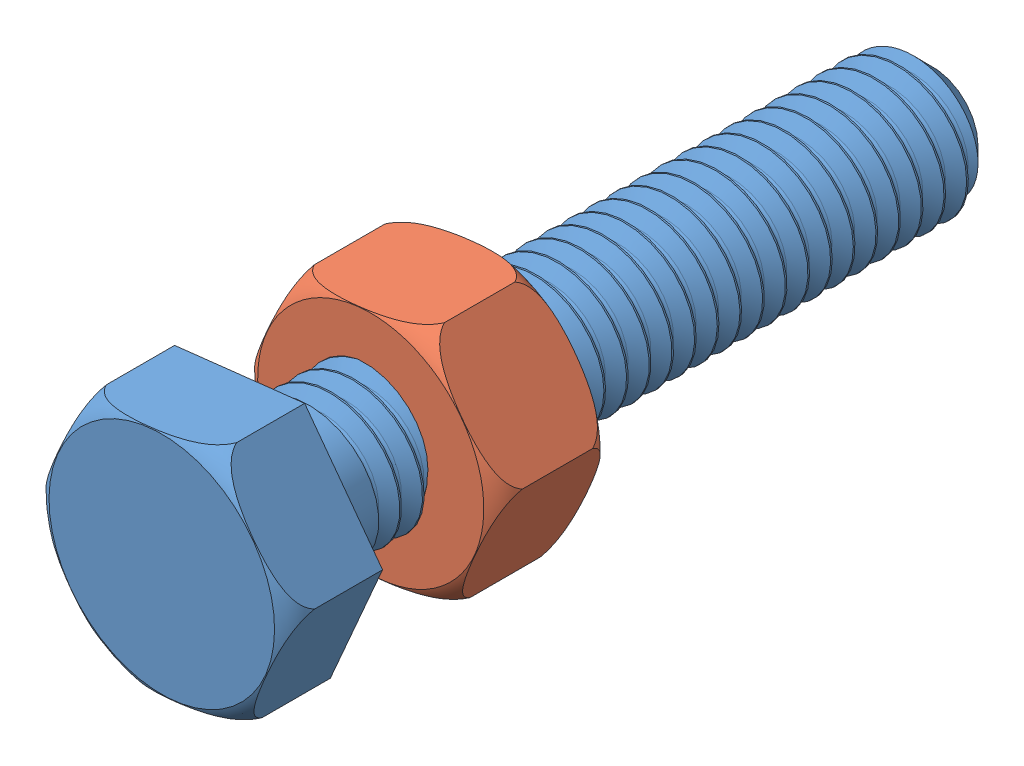
SolidWorks assembly Ensamblaje1, configuration Predeterminado. Lengths in mm.
Overall size (14.33 13.45 34.38).
2 component instances, 2 part files, 2 mates.
Components (placement in the parent):
- cıvata1-1: cıvata1 [Varsayılan] at (-0.8897 0.5502 17.1925) size (12.49 11.6 34.38)
- cıvata-1: cıvata [Varsayılan] at (-0.8897 0.5502 36.9758) x (0.986761 0.162178 0) z (0 0 1) size (12.63 11.55 5.99)
Mates (geometry in assembly coordinates):
- Coincidente3: coincident aligned: plane of cıvata1-1 through (-6.6261 -0.1032 51.1925) normal (-0.80387 -0.594805 0); plane of cıvata-1 through (-6.6261 -0.1032 41.9758) normal (-0.80387 -0.594805 0)
- Coincidente4: coincident aligned: plane of cıvata1-1 through (-3.192 -4.7444 51.1925) normal (0.113181 -0.993574 0); plane of cıvata-1 through (-3.192 -4.7444 41.9758) normal (0.113181 -0.993574 0)
